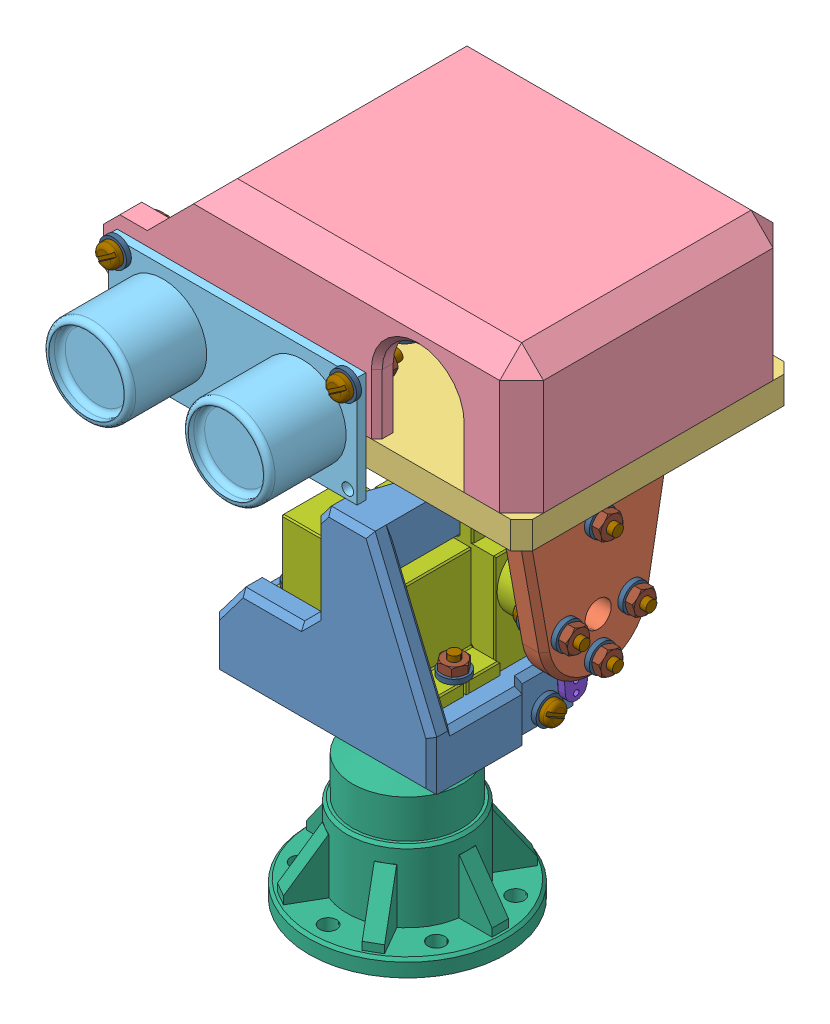
SolidWorks assembly headSub, configuration Default. Lengths in mm.
Overall size (76.5 110.09 65.6).
65 component instances, 11 part files, 135 mates.
Components (placement in the parent):
- headServoMount-1: headServoMount [Default] at (-6.1591 24.2018 19.2288) x (-1 0 0) z (0 0 1) size (39.75 36.12 28.6)
- headMount-1: headMount [Default] at (6.6839 24.3518 6.3351) x (0 -1 0) z (1 0 0) size (40 30 34)
- headBaseplate-1: headBaseplate [Default] at (24.6839 48.7958 -21.2212) x (-1 0 0) z (0 0 -1) size (60 5 50)
- headCanopy-1: headCanopy [Default] at (24.6839 78.7958 28.7788) x (-1 0 0) z (0 -1 0) size (76.5 50 25)
- usSensor-2: usSensor [Default] at (-49.3161 43.5958 28.7788) x (1 0 0) z (0 -1 0) size (45.5 15.6 26.2)
- mastMount-top-1: mastMount-top [Default] at (-11.9091 -31.2972 13.0788) size (36 28 36)
- sg90Servo-1: sg90Servo [Default] at (-6.1591 24.0708 19.2288) x (-1 0 0) z (0 0 1) size (32.7 29.37 12.3)
- sg90Servo-2: sg90Servo [Default] at (-24.2841 24.5458 6.9288) x (0 -1 0) z (0 0 1) size (32.7 29.37 12.3)
- sg90ServoHorn-star-1: sg90ServoHorn-star [Default] at (6.6839 20.6958 -2.0712) x (0 -1 0) z (0 0 -1) size (34.4 4 15.7)
- pan slot head_am-1: pan slot head_am [B18.6.7M - M3 x 0.5 x 16 Slotted PHMS --16C] at (-4.3161 42.4958 8.2249) x (0 1 0) z (0.26276 0 -0.964861) size (18.4 5.6 5.6)
- flat washer narrow_am-1: flat washer narrow_am [B18.22M - Plain washer, 3 mm, narrow] at (-4.3161 54.6958 8.2249) x (0 1 0) z (-0.26276 0 0.964861) size (0.9 7 7)
- flat washer narrow_am-2: flat washer narrow_am [B18.22M - Plain washer, 3 mm, narrow] at (-4.3161 45.7958 8.2249) x (0 1 0) z (-0.26276 0 0.964861) size (0.9 7 7)
- hex nut style 1_am-1: hex nut style 1_am [B18.2.4.1M - Hex nut, Style 1,  M3 x 0.5 --D-C] at (-4.3161 57.0958 8.2249) x (-0.26276 0 0.964861) z (0 1 0) size (5.5 6.35 2.4)
- pan slot head_am-2: pan slot head_am [B18.6.7M - M3 x 0.5 x 16 Slotted PHMS --16C] at (-17.3161 42.4958 8.2249) x (0 1 0) z (0.26276 0 -0.964861) size (18.4 5.6 5.6)
- flat washer narrow_am-3: flat washer narrow_am [B18.22M - Plain washer, 3 mm, narrow] at (-17.3161 54.6958 8.2249) x (0 1 0) z (-0.26276 0 0.964861) size (0.9 7 7)
- flat washer narrow_am-4: flat washer narrow_am [B18.22M - Plain washer, 3 mm, narrow] at (-17.3161 45.7958 8.2249) x (0 1 0) z (-0.26276 0 0.964861) size (0.9 7 7)
- hex nut style 1_am-2: hex nut style 1_am [B18.2.4.1M - Hex nut, Style 1,  M3 x 0.5 --D-C] at (-17.3161 57.0958 8.2249) x (-0.26276 0 0.964861) z (0 1 0) size (5.5 6.35 2.4)
- pan slot head_am-3: pan slot head_am [B18.6.7M - M3 x 0.5 x 16 Slotted PHMS --16C] at (-17.3161 42.4958 -2.7121) x (0 1 0) z (0.26276 0 -0.964861) size (18.4 5.6 5.6)
- flat washer narrow_am-5: flat washer narrow_am [B18.22M - Plain washer, 3 mm, narrow] at (-17.3161 54.6958 -2.7121) x (0 1 0) z (-0.26276 0 0.964861) size (0.9 7 7)
- flat washer narrow_am-6: flat washer narrow_am [B18.22M - Plain washer, 3 mm, narrow] at (-17.3161 45.7958 -2.7121) x (0 1 0) z (-0.26276 0 0.964861) size (0.9 7 7)
- hex nut style 1_am-3: hex nut style 1_am [B18.2.4.1M - Hex nut, Style 1,  M3 x 0.5 --D-C] at (-17.3161 57.0958 -2.7121) x (-0.26276 0 0.964861) z (0 1 0) size (5.5 6.35 2.4)
- pan slot head_am-4: pan slot head_am [B18.6.7M - M3 x 0.5 x 16 Slotted PHMS --16C] at (-4.3161 42.4958 -2.7121) x (0 1 0) z (0.26276 0 -0.964861) size (18.4 5.6 5.6)
- flat washer narrow_am-7: flat washer narrow_am [B18.22M - Plain washer, 3 mm, narrow] at (-4.3161 54.6958 -2.7121) x (0 1 0) z (-0.26276 0 0.964861) size (0.9 7 7)
- flat washer narrow_am-8: flat washer narrow_am [B18.22M - Plain washer, 3 mm, narrow] at (-4.3161 45.7958 -2.7121) x (0 1 0) z (-0.26276 0 0.964861) size (0.9 7 7)
- hex nut style 1_am-4: hex nut style 1_am [B18.2.4.1M - Hex nut, Style 1,  M3 x 0.5 --D-C] at (-4.3161 57.0958 -2.7121) x (-0.26276 0 0.964861) z (0 1 0) size (5.5 6.35 2.4)
- pan slot head_am-5: pan slot head_am [B18.6.7M - M2 x 0.4 x 16 Slotted PHMS --16C] at (3.4409 -0.9542 0.7788) x (-1 0 0) z (0 -0.479221 -0.877694) size (17.6 4 4)
- flat washer narrow_am-9: flat washer narrow_am [B18.22M - Plain washer, 2 mm, narrow] at (0.9409 -0.9542 0.7788) x (-1 0 0) z (0 -0.479221 -0.877694) size (0.9 5 5)
- flat washer narrow_am-10: flat washer narrow_am [B18.22M - Plain washer, 2 mm, narrow] at (-9.5591 -0.9542 0.7788) x (-1 0 0) z (0 -0.479221 -0.877694) size (0.9 5 5)
- hex nut style 1_am-5: hex nut style 1_am [B18.2.4.1M - Hex nut, Style 1,  M2 x 0.4 --D-C] at (-11.1591 -0.9542 0.7788) x (0 0.479221 0.877694) z (-1 0 0) size (4 4.62 1.6)
- pan slot head_am-7: pan slot head_am [B18.6.7M - M2 x 0.4 x 10 Slotted PHMS --10C] at (-3.6591 27.3458 0.7788) x (-1 0 0) z (0 -0.054009 -0.99854) size (11.6 4 4)
- flat washer narrow_am-13: flat washer narrow_am [B18.22M - Plain washer, 2 mm, narrow] at (-6.1591 27.3458 0.7788) x (-1 0 0) z (0 -0.054009 -0.99854) size (0.9 5 5)
- flat washer narrow_am-14: flat washer narrow_am [B18.22M - Plain washer, 2 mm, narrow] at (-12.5591 27.3458 0.7788) x (-1 0 0) z (0 -0.054009 -0.99854) size (0.9 5 5)
- hex nut style 1_am-7: hex nut style 1_am [B18.2.4.1M - Hex nut, Style 1,  M2 x 0.4 --D-C] at (-14.1591 27.3458 0.7788) x (0 0.054009 0.99854) z (-1 0 0) size (4 4.62 1.6)
- pan slot head_am-8: pan slot head_am [B18.6.7M - M2 x 0.4 x 10 Slotted PHMS --10C] at (-31.6591 10.9458 13.0788) x (0 -1 0) z (-0.98388 0 -0.178829) size (11.6 4 4)
- flat washer narrow_am-15: flat washer narrow_am [B18.22M - Plain washer, 2 mm, narrow] at (-31.6591 8.4458 13.0788) x (0 -1 0) z (-0.98388 0 -0.178829) size (0.9 5 5)
- flat washer narrow_am-16: flat washer narrow_am [B18.22M - Plain washer, 2 mm, narrow] at (-31.6591 2.0458 13.0788) x (0 -1 0) z (-0.98388 0 -0.178829) size (0.9 5 5)
- hex nut style 1_am-8: hex nut style 1_am [B18.2.4.1M - Hex nut, Style 1,  M2 x 0.4 --D-C] at (-31.6591 0.4458 13.0788) x (0.98388 0 0.178829) z (0 -1 0) size (4 4.62 1.6)
- pan slot head_am-9: pan slot head_am [B18.6.7M - M2 x 0.4 x 16 Slotted PHMS --16C] at (-3.3591 -5.6542 13.0788) x (0 1 0) z (-0.921484 0 -0.388417) size (17.6 4 4)
- flat washer narrow_am-17: flat washer narrow_am [B18.22M - Plain washer, 2 mm, narrow] at (-3.3591 -3.1542 13.0788) x (0 1 0) z (-0.921484 0 -0.388417) size (0.9 5 5)
- flat washer narrow_am-18: flat washer narrow_am [B18.22M - Plain washer, 2 mm, narrow] at (-3.3591 9.3458 13.0788) x (0 1 0) z (-0.970412 0 0.241457) size (0.9 5 5)
- hex nut style 1_am-9: hex nut style 1_am [B18.2.4.1M - Hex nut, Style 1,  M2 x 0.4 --D-C] at (-3.3591 10.9458 13.0788) x (0.921484 0 0.388417) z (0 1 0) size (4 4.62 1.6)
- flat washer narrow_am-19: flat washer narrow_am [B18.22M - Plain washer, 2 mm, narrow] at (5.2239 33.7958 0.7788) x (1 0 0) z (0 -0.958974 0.283495) size (0.9 5 5)
- flat washer narrow_am-20: flat washer narrow_am [B18.22M - Plain washer, 2 mm, narrow] at (11.5839 33.7958 0.7788) x (1 0 0) z (0 -0.958974 0.283495) size (0.9 5 5)
- hex nut style 1_am-10: hex nut style 1_am [B18.2.4.1M - Hex nut, Style 1,  M2 x 0.4 --D-C] at (13.1839 33.7958 0.7788) x (0 0.958974 -0.283495) z (1 0 0) size (4 4.62 1.6)
- pan slot head_am-10: pan slot head_am [B18.6.7M - M2 x 0.4 x 10 Slotted PHMS --10C] at (2.7239 33.7958 0.7788) x (1 0 0) z (0 -0.958974 0.283495) size (11.6 4 4)
- flat washer narrow_am-21: flat washer narrow_am [B18.22M - Plain washer, 2 mm, narrow] at (5.2239 18.7958 6.8788) x (1 0 0) z (0 -0.958974 0.283495) size (0.9 5 5)
- flat washer narrow_am-22: flat washer narrow_am [B18.22M - Plain washer, 2 mm, narrow] at (11.5839 18.7958 6.8788) x (1 0 0) z (0 -0.958974 0.283495) size (0.9 5 5)
- hex nut style 1_am-11: hex nut style 1_am [B18.2.4.1M - Hex nut, Style 1,  M2 x 0.4 --D-C] at (13.1839 18.7958 6.8788) x (0 0.958974 -0.283495) z (1 0 0) size (4 4.62 1.6)
- pan slot head_am-11: pan slot head_am [B18.6.7M - M2 x 0.4 x 10 Slotted PHMS --10C] at (2.7239 18.7958 6.8788) x (1 0 0) z (0 -0.958974 0.283495) size (11.6 4 4)
- flat washer narrow_am-23: flat washer narrow_am [B18.22M - Plain washer, 2 mm, narrow] at (5.2239 12.2958 0.7788) x (1 0 0) z (0 -0.958974 0.283495) size (0.9 5 5)
- flat washer narrow_am-24: flat washer narrow_am [B18.22M - Plain washer, 2 mm, narrow] at (11.5839 12.2958 0.7788) x (1 0 0) z (0 -0.958974 0.283495) size (0.9 5 5)
- hex nut style 1_am-12: hex nut style 1_am [B18.2.4.1M - Hex nut, Style 1,  M2 x 0.4 --D-C] at (13.1839 12.2958 0.7788) x (0 0.958974 -0.283495) z (1 0 0) size (4 4.62 1.6)
- pan slot head_am-12: pan slot head_am [B18.6.7M - M2 x 0.4 x 10 Slotted PHMS --10C] at (2.7239 12.2958 0.7788) x (1 0 0) z (0 -0.958974 0.283495) size (11.6 4 4)
- flat washer narrow_am-25: flat washer narrow_am [B18.22M - Plain washer, 2 mm, narrow] at (5.2239 18.7958 -5.3212) x (1 0 0) z (0 -0.958974 0.283495) size (0.9 5 5)
- flat washer narrow_am-26: flat washer narrow_am [B18.22M - Plain washer, 2 mm, narrow] at (11.5839 18.7958 -5.3212) x (1 0 0) z (0 -0.958974 0.283495) size (0.9 5 5)
- hex nut style 1_am-13: hex nut style 1_am [B18.2.4.1M - Hex nut, Style 1,  M2 x 0.4 --D-C] at (13.1839 18.7958 -5.3212) x (0 0.958974 -0.283495) z (1 0 0) size (4 4.62 1.6)
- pan slot head_am-13: pan slot head_am [B18.6.7M - M2 x 0.4 x 10 Slotted PHMS --10C] at (2.7239 18.7958 -5.3212) x (1 0 0) z (0 -0.958974 0.283495) size (11.6 4 4)
- flat washer narrow_am-27: flat washer narrow_am [B18.22M - Plain washer, 2 mm, narrow] at (-5.5161 62.0958 30.3788) x (0 0 -1) z (-0.825588 -0.564273 0) size (0.9 5 5)
- flat washer narrow_am-28: flat washer narrow_am [B18.22M - Plain washer, 2 mm, narrow] at (-5.5161 62.0958 24.8788) x (0 0 -1) z (-0.825588 -0.564273 0) size (0.9 5 5)
- hex nut style 1_am-14: hex nut style 1_am [B18.2.4.1M - Hex nut, Style 1,  M2 x 0.4 --D-C] at (-5.5161 62.0958 23.2788) x (0.825588 0.564273 0) z (0 0 -1) size (4 4.62 1.6)
- pan slot head_am-14: pan slot head_am [B18.6.7M - M2 x 0.4 x 10 Slotted PHMS --10C] at (-5.5161 62.0958 32.8788) x (0 0 -1) z (-0.825588 -0.564273 0) size (11.6 4 4)
- flat washer narrow_am-29: flat washer narrow_am [B18.22M - Plain washer, 2 mm, narrow] at (-47.6161 62.0958 30.3788) x (0 0 -1) z (-0.825588 -0.564273 0) size (0.9 5 5)
- flat washer narrow_am-30: flat washer narrow_am [B18.22M - Plain washer, 2 mm, narrow] at (-47.6161 62.0958 23.8788) x (0 0 -1) z (-0.825588 -0.564273 0) size (0.9 5 5)
- hex nut style 1_am-15: hex nut style 1_am [B18.2.4.1M - Hex nut, Style 1,  M2 x 0.4 --D-C] at (-47.6161 62.0958 22.2788) x (0.825588 0.564273 0) z (0 0 -1) size (4 4.62 1.6)
- pan slot head_am-15: pan slot head_am [B18.6.7M - M2 x 0.4 x 10 Slotted PHMS --10C] at (-47.6161 62.0958 32.8788) x (0 0 -1) z (-0.825588 -0.564273 0) size (11.6 4 4)
Mates (geometry in assembly coordinates):
- Parallel8: parallel aligned: plane of headMount-1 through (10.6839 24.3518 6.3351) normal (1 0 0); plane of headBaseplate-1 through (24.6839 53.7958 -21.2212) normal (1 0 0)
- Coincident41: coincident anti-aligned: plane of headMount-1 through (10.6839 48.7958 6.3351) normal (0 1 0); plane of headBaseplate-1 through (24.6839 48.7958 -21.2212) normal (0 -1 0)
- Coincident45: coincident anti-aligned: plane of headBaseplate-1 through (24.6839 53.7958 -21.2212) normal (0 1 0); plane of headCanopy-1 through (24.6839 53.7958 28.7788) normal (0 -1 0)
- Distance10: distance = 12 mm aligned: plane of headMount-1 through (-23.3161 24.3518 6.3351) normal (-1 0 0); plane of headBaseplate-1 through (-35.3161 53.7958 -21.2212) normal (-1 0 0)
- Distance11: distance = 13 mm aligned: plane of headBaseplate-1 through (24.6839 53.7958 28.7788) normal (0 0 1); plane of headMount-1 through (10.6839 24.3518 15.7788) normal (0 0 1)
- Concentric3: concentric anti-aligned: cylinder of headBaseplate-1 through (20.1839 51.7958 24.2788) axis (0 1 0) radius 1.55; cylinder of headCanopy-1 through (20.1839 55.7958 24.2788) axis (0 -1 0) radius 1.55
- Concentric4: concentric anti-aligned: cylinder of headBaseplate-1 through (-30.8161 51.7958 -16.7212) axis (0 1 0) radius 1.55; cylinder of headCanopy-1 through (-30.8161 55.7958 -16.7212) axis (0 -1 0) radius 1.55
- Coincident63: coincident anti-aligned: plane of headCanopy-1 through (-35.3161 73.7958 28.7788) normal (0 0 1); plane of usSensor-2 through (-49.3161 43.5958 28.7788) normal (0 0 -1)
- Distance17: distance = 15 mm aligned: plane of usSensor-2 through (-49.3161 63.7958 30.3788) normal (0 1 0); plane of headCanopy-1 through (24.6839 78.7958 28.7788) normal (0 1 0)
- Distance18: distance = 2 mm aligned: plane of usSensor-2 through (-3.8161 43.5958 30.3788) normal (1 0 0); plane of headCanopy-1 through (-1.8161 78.7958 -21.2222) normal (1 0 0)
- Coincident66: coincident anti-aligned: plane of headServoMount-1 through (-6.1591 24.2018 19.2288) normal (0 0 -1); plane of sg90Servo-1 through (-6.1591 1.8458 19.2288) normal (0 0 1)
- Coincident67: coincident anti-aligned: plane of sg90Servo-1 through (-6.1591 1.8458 6.9288) normal (0 0 -1); plane of sg90Servo-2 through (-2.0591 24.5458 6.9288) normal (0 0 1)
- Coincident68: coincident aligned: plane of sg90Servo-1 through (-6.1591 1.8458 19.2288) normal (1 0 0); plane of sg90Servo-2 through (-6.1591 -3.1542 6.9288) normal (1 0 0)
- Coincident69: coincident aligned: plane of sg90Servo-1 through (-6.1591 1.8458 19.2288) normal (0 -1 0); plane of sg90Servo-2 through (-2.0591 1.8458 6.9288) normal (0 -1 0)
- Concentric8: concentric anti-aligned: cylinder of headServoMount-1 through (-31.6591 -3.1552 13.0788) axis (0 1 0) radius 1.1; cylinder of sg90Servo-1 through (-31.6591 24.0719 13.0788) axis (0 -1 0) radius 1.1
- Coincident71: coincident anti-aligned: plane of headServoMount-1 through (-6.1591 5.9458 -1.8849) normal (0 1 0); plane of sg90Servo-1 through (-33.8591 5.9458 19.2288) normal (0 -1 0)
- Concentric9: concentric aligned: cylinder of mastMount-top-1 through (-11.9091 -5.2972 13.0788) axis (0 1 0) radius 2.4; cylinder of sg90Servo-1 through (-11.9091 -5.2972 13.0788) axis (0 1 0) radius 1.984
- Coincident72: coincident anti-aligned: plane of mastMount-top-1 through (-11.9091 -5.2972 13.0788) normal (0 1 0); plane of sg90Servo-1 through (-11.9091 -5.2972 13.0788) normal (0 -1 0)
- Coincident73: coincident anti-aligned: plane of headMount-1 through (6.6839 24.3518 6.3351) normal (-1 0 0); plane of sg90ServoHorn-star-1 through (6.6839 20.6958 -2.0712) normal (1 0 0)
- Parallel9: parallel anti-aligned: plane of headMount-1 through (-23.3161 45.7958 -14.2212) normal (0 -1 0); plane of sg90ServoHorn-star-1 through (5.2239 20.6958 -2.0712) normal (0 1 0)
- Concentric12: concentric aligned: cylinder of headMount-1 through (10.6849 18.7958 0.7788) axis (-1 0 0) radius 2.4; cylinder of sg90ServoHorn-star-1 through (6.6849 18.7958 0.7788) axis (-1 0 0) radius 1.2
- Concentric13: concentric aligned: cylinder of sg90Servo-2 through (5.0839 18.7958 0.7788) axis (-1 0 0) radius 1.984; cylinder of sg90ServoHorn-star-1 through (5.0839 18.7958 0.7788) axis (-1 0 0) radius 2.4
- Coincident78: coincident anti-aligned: plane of sg90Servo-2 through (5.0839 18.7958 0.7788) normal (1 0 0); plane of sg90ServoHorn-star-1 through (5.0839 18.7958 0.7788) normal (-1 0 0)
- Concentric14: concentric aligned: cylinder of pan slot head_am-1 through (-4.3161 17.0958 8.2249) axis (0 -1 0) radius 1.5; circle of flat washer narrow_am-2
- Coincident79: coincident anti-aligned: plane of pan slot head_am-1 through (-2.8688 44.8958 8.619) normal (0 1 0); plane of flat washer narrow_am-2 through (-7.6931 44.8958 7.3052) normal (0 -1 0)
- Concentric15: concentric aligned: cylinder of pan slot head_am-1 through (-4.3161 17.0958 8.2249) axis (0 -1 0) radius 1.5; cylinder of flat washer narrow_am-1 through (-4.3161 19.7708 8.2249) axis (0 -1 0) radius 1.84
- Concentric16: concentric anti-aligned: cylinder of pan slot head_am-1 through (-4.3161 17.0958 8.2249) axis (0 -1 0) radius 1.5; cylinder of hex nut style 1_am-1 through (-4.3161 54.6958 8.2249) axis (0 1 0) radius 1.25
- Coincident80: coincident anti-aligned: plane of flat washer narrow_am-1 through (-6.0914 54.6958 7.7414) normal (0 1 0); plane of hex nut style 1_am-1 through (-1.2522 54.6958 9.0593) normal (0 -1 0)
- Concentric17: concentric aligned: cylinder of headMount-1 through (-4.3161 48.7968 8.2249) axis (0 -1 0) radius 1.55; cylinder of pan slot head_am-1 through (-4.3161 17.0958 8.2249) axis (0 -1 0) radius 1.5
- Coincident81: coincident anti-aligned: plane of headMount-1 through (-23.3161 45.7958 -14.2212) normal (0 -1 0); plane of flat washer narrow_am-2 through (-6.0914 45.7958 7.7414) normal (0 1 0)
- Coincident82: coincident anti-aligned: plane of headBaseplate-1 through (24.6839 53.7958 -21.2212) normal (0 1 0); plane of flat washer narrow_am-1 through (-7.6931 53.7958 7.3052) normal (0 -1 0)
- Concentric18: concentric aligned: cylinder of pan slot head_am-2 through (-17.3161 17.0958 8.2249) axis (0 -1 0) radius 1.5; circle of flat washer narrow_am-4
- Coincident83: coincident anti-aligned: plane of pan slot head_am-2 through (-15.8688 44.8958 8.619) normal (0 1 0); plane of flat washer narrow_am-4 through (-20.6931 44.8958 7.3052) normal (0 -1 0)
- Concentric19: concentric aligned: cylinder of pan slot head_am-2 through (-17.3161 17.0958 8.2249) axis (0 -1 0) radius 1.5; cylinder of flat washer narrow_am-3 through (-17.3161 19.7708 8.2249) axis (0 -1 0) radius 1.84
- Concentric20: concentric anti-aligned: cylinder of pan slot head_am-2 through (-17.3161 17.0958 8.2249) axis (0 -1 0) radius 1.5; cylinder of hex nut style 1_am-2 through (-17.3161 54.6958 8.2249) axis (0 1 0) radius 1.25
- Coincident84: coincident anti-aligned: plane of flat washer narrow_am-3 through (-19.0914 54.6958 7.7414) normal (0 1 0); plane of hex nut style 1_am-2 through (-14.2522 54.6958 9.0593) normal (0 -1 0)
- Concentric21: concentric aligned: cylinder of headMount-1 through (-17.3161 48.7968 8.2249) axis (0 -1 0) radius 1.55; cylinder of pan slot head_am-2 through (-17.3161 17.0958 8.2249) axis (0 -1 0) radius 1.5
- Coincident85: coincident anti-aligned: plane of headMount-1 through (-23.3161 45.7958 -14.2212) normal (0 -1 0); plane of flat washer narrow_am-4 through (-19.0914 45.7958 7.7414) normal (0 1 0)
- Coincident86: coincident anti-aligned: plane of headBaseplate-1 through (24.6839 53.7958 -21.2212) normal (0 1 0); plane of flat washer narrow_am-3 through (-20.6931 53.7958 7.3052) normal (0 -1 0)
- Concentric22: concentric aligned: cylinder of pan slot head_am-3 through (-17.3161 17.0958 -2.7121) axis (0 -1 0) radius 1.5; circle of flat washer narrow_am-6
- Coincident87: coincident anti-aligned: plane of pan slot head_am-3 through (-15.8688 44.8958 -2.318) normal (0 1 0); plane of flat washer narrow_am-6 through (-20.6931 44.8958 -3.6318) normal (0 -1 0)
- Concentric23: concentric aligned: cylinder of pan slot head_am-3 through (-17.3161 17.0958 -2.7121) axis (0 -1 0) radius 1.5; cylinder of flat washer narrow_am-5 through (-17.3161 19.7708 -2.7121) axis (0 -1 0) radius 1.84
- Concentric24: concentric anti-aligned: cylinder of pan slot head_am-3 through (-17.3161 17.0958 -2.7121) axis (0 -1 0) radius 1.5; cylinder of hex nut style 1_am-3 through (-17.3161 54.6958 -2.7121) axis (0 1 0) radius 1.25
- Coincident88: coincident anti-aligned: plane of flat washer narrow_am-5 through (-19.0914 54.6958 -3.1956) normal (0 1 0); plane of hex nut style 1_am-3 through (-14.2522 54.6958 -1.8778) normal (0 -1 0)
- Concentric25: concentric aligned: cylinder of headMount-1 through (-17.3161 48.7968 -2.7121) axis (0 -1 0) radius 1.55; cylinder of pan slot head_am-3 through (-17.3161 17.0958 -2.7121) axis (0 -1 0) radius 1.5
- Coincident89: coincident anti-aligned: plane of headMount-1 through (-23.3161 45.7958 -14.2212) normal (0 -1 0); plane of flat washer narrow_am-6 through (-19.0914 45.7958 -3.1956) normal (0 1 0)
- Coincident90: coincident anti-aligned: plane of headBaseplate-1 through (24.6839 53.7958 -21.2212) normal (0 1 0); plane of flat washer narrow_am-5 through (-20.6931 53.7958 -3.6318) normal (0 -1 0)
- Concentric26: concentric aligned: cylinder of pan slot head_am-4 through (-4.3161 17.0958 -2.7121) axis (0 -1 0) radius 1.5; circle of flat washer narrow_am-8
- Coincident91: coincident anti-aligned: plane of pan slot head_am-4 through (-2.8688 44.8958 -2.318) normal (0 1 0); plane of flat washer narrow_am-8 through (-7.6931 44.8958 -3.6318) normal (0 -1 0)
- Concentric27: concentric aligned: cylinder of pan slot head_am-4 through (-4.3161 17.0958 -2.7121) axis (0 -1 0) radius 1.5; cylinder of flat washer narrow_am-7 through (-4.3161 19.7708 -2.7121) axis (0 -1 0) radius 1.84
- Concentric28: concentric anti-aligned: cylinder of pan slot head_am-4 through (-4.3161 17.0958 -2.7121) axis (0 -1 0) radius 1.5; cylinder of hex nut style 1_am-4 through (-4.3161 54.6958 -2.7121) axis (0 1 0) radius 1.25
- Coincident92: coincident anti-aligned: plane of flat washer narrow_am-7 through (-6.0914 54.6958 -3.1956) normal (0 1 0); plane of hex nut style 1_am-4 through (-1.2522 54.6958 -1.8778) normal (0 -1 0)
- Concentric29: concentric aligned: cylinder of headMount-1 through (-4.3161 48.7968 -2.7121) axis (0 -1 0) radius 1.55; cylinder of pan slot head_am-4 through (-4.3161 17.0958 -2.7121) axis (0 -1 0) radius 1.5
- Coincident93: coincident anti-aligned: plane of headMount-1 through (-23.3161 45.7958 -14.2212) normal (0 -1 0); plane of flat washer narrow_am-8 through (-6.0914 45.7958 -3.1956) normal (0 1 0)
- Coincident94: coincident anti-aligned: plane of headBaseplate-1 through (24.6839 53.7958 -21.2212) normal (0 1 0); plane of flat washer narrow_am-7 through (-7.6931 53.7958 -3.6318) normal (0 -1 0)
- Concentric30: concentric aligned: cylinder of pan slot head_am-5 through (28.8409 -0.9542 0.7788) axis (1 0 0) radius 1; cylinder of flat washer narrow_am-9 through (35.8659 -0.9542 0.7788) axis (1 0 0) radius 1.32
- Concentric32: concentric aligned: cylinder of pan slot head_am-5 through (28.8409 -0.9542 0.7788) axis (1 0 0) radius 1; cylinder of flat washer narrow_am-10 through (25.3659 -0.9542 0.7788) axis (1 0 0) radius 1.32
- Coincident95: coincident anti-aligned: plane of pan slot head_am-5 through (1.8409 -0.0765 0.2996) normal (-1 0 0); plane of flat washer narrow_am-9 through (1.8409 1.2401 -0.4192) normal (1 0 0)
- Concentric33: concentric anti-aligned: cylinder of pan slot head_am-5 through (28.8409 -0.9542 0.7788) axis (1 0 0) radius 1; cylinder of hex nut style 1_am-5 through (-9.5591 -0.9542 0.7788) axis (-1 0 0) radius 0.8
- Coincident96: coincident anti-aligned: plane of flat washer narrow_am-10 through (-9.5591 0.2044 0.1463) normal (-1 0 0); plane of hex nut style 1_am-5 through (-9.5591 1.0728 -0.3279) normal (1 0 0)
- Concentric34: concentric anti-aligned: cylinder of headServoMount-1 through (2.6044 -0.9542 0.7788) axis (-1 0 0) radius 1.1; cylinder of pan slot head_am-5 through (28.8409 -0.9542 0.7788) axis (1 0 0) radius 1
- Coincident97: coincident anti-aligned: plane of headServoMount-1 through (0.9409 24.2018 -16.9133) normal (1 0 0); plane of flat washer narrow_am-9 through (0.9409 0.2044 0.1463) normal (-1 0 0)
- Coincident98: coincident anti-aligned: plane of sg90Servo-2 through (-8.6591 -3.1542 6.9288) normal (-1 0 0); plane of flat washer narrow_am-10 through (-8.6591 1.2401 -0.4192) normal (1 0 0)
- Concentric39: concentric aligned: cylinder of pan slot head_am-7 through (21.7409 27.3458 0.7788) axis (1 0 0) radius 1; cylinder of flat washer narrow_am-13 through (28.7659 27.3458 0.7788) axis (1 0 0) radius 1.32
- Concentric40: concentric aligned: cylinder of pan slot head_am-7 through (21.7409 27.3458 0.7788) axis (1 0 0) radius 1; cylinder of flat washer narrow_am-14 through (22.3659 27.3458 0.7788) axis (1 0 0) radius 1.32
- Coincident102: coincident anti-aligned: plane of pan slot head_am-7 through (-5.2591 28.3444 0.7248) normal (-1 0 0); plane of flat washer narrow_am-13 through (-5.2591 29.8422 0.6438) normal (1 0 0)
- Concentric41: concentric anti-aligned: cylinder of pan slot head_am-7 through (21.7409 27.3458 0.7788) axis (1 0 0) radius 1; cylinder of hex nut style 1_am-7 through (-12.5591 27.3458 0.7788) axis (-1 0 0) radius 0.8
- Coincident103: coincident anti-aligned: plane of flat washer narrow_am-14 through (-12.5591 28.6639 0.7075) normal (-1 0 0); plane of hex nut style 1_am-7 through (-12.5591 29.6519 0.6541) normal (1 0 0)
- Concentric42: concentric aligned: cylinder of headServoMount-1 through (-37.1476 27.3458 0.7788) axis (1 0 0) radius 1.1; cylinder of pan slot head_am-7 through (21.7409 27.3458 0.7788) axis (1 0 0) radius 1
- Coincident104: coincident anti-aligned: plane of sg90Servo-2 through (-6.1591 29.5458 6.9288) normal (1 0 0); plane of flat washer narrow_am-13 through (-6.1591 28.6639 0.7075) normal (-1 0 0)
- Coincident105: coincident anti-aligned: plane of headServoMount-1 through (-11.6591 24.2018 -14.0731) normal (-1 0 0); plane of flat washer narrow_am-14 through (-11.6591 29.8422 0.6438) normal (1 0 0)
- Concentric43: concentric aligned: cylinder of pan slot head_am-8 through (-31.6591 36.3458 13.0788) axis (0 1 0) radius 1; cylinder of flat washer narrow_am-15 through (-31.6591 43.3708 13.0788) axis (0 1 0) radius 1.32
- Concentric44: concentric aligned: cylinder of pan slot head_am-8 through (-31.6591 36.3458 13.0788) axis (0 1 0) radius 1; cylinder of flat washer narrow_am-16 through (-31.6591 36.9708 13.0788) axis (0 1 0) radius 1.32
- Coincident106: coincident anti-aligned: plane of pan slot head_am-8 through (-31.8379 9.3458 14.0627) normal (0 -1 0); plane of flat washer narrow_am-15 through (-32.1061 9.3458 15.5385) normal (0 1 0)
- Concentric45: concentric anti-aligned: cylinder of pan slot head_am-8 through (-31.6591 36.3458 13.0788) axis (0 1 0) radius 1; cylinder of hex nut style 1_am-8 through (-31.6591 2.0458 13.0788) axis (0 -1 0) radius 0.8
- Coincident107: coincident anti-aligned: plane of flat washer narrow_am-16 through (-31.8951 2.0458 14.3776) normal (0 -1 0); plane of hex nut style 1_am-8 through (-32.0721 2.0458 15.351) normal (0 1 0)
- Concentric46: concentric aligned: cylinder of headServoMount-1 through (-31.6591 -3.1552 13.0788) axis (0 1 0) radius 1.1; cylinder of pan slot head_am-8 through (-31.6591 36.3458 13.0788) axis (0 1 0) radius 1
- Coincident108: coincident anti-aligned: plane of sg90Servo-1 through (-33.8591 8.4458 19.2288) normal (0 1 0); plane of flat washer narrow_am-15 through (-31.8951 8.4458 14.3776) normal (0 -1 0)
- Coincident109: coincident anti-aligned: plane of headServoMount-1 through (-6.1591 2.9458 -1.8849) normal (0 -1 0); plane of flat washer narrow_am-16 through (-32.1061 2.9458 15.5385) normal (0 1 0)
- Concentric47: concentric aligned: cylinder of pan slot head_am-9 through (-3.3591 -31.0542 13.0788) axis (0 -1 0) radius 1; cylinder of flat washer narrow_am-17 through (-3.3591 -38.0792 13.0788) axis (0 -1 0) radius 1.32
- Concentric48: concentric aligned: cylinder of pan slot head_am-9 through (-3.3591 -31.0542 13.0788) axis (0 -1 0) radius 1; cylinder of flat washer narrow_am-18 through (-3.3591 -25.5792 13.0788) axis (0 -1 0) radius 1.32
- Coincident110: coincident anti-aligned: plane of pan slot head_am-9 through (-2.9707 -4.0542 12.1574) normal (0 1 0); plane of flat washer narrow_am-17 through (-2.388 -4.0542 10.7751) normal (0 -1 0)
- Concentric49: concentric anti-aligned: cylinder of pan slot head_am-9 through (-3.3591 -31.0542 13.0788) axis (0 -1 0) radius 1; cylinder of hex nut style 1_am-9 through (-3.3591 9.3458 13.0788) axis (0 1 0) radius 0.8
- Coincident111: coincident anti-aligned: plane of flat washer narrow_am-18 through (-3.6778 9.3458 11.7979) normal (0 1 0); plane of hex nut style 1_am-9 through (-2.4621 9.3458 10.9508) normal (0 -1 0)
- Concentric50: concentric anti-aligned: cylinder of headServoMount-1 through (-3.3591 -3.1552 13.0788) axis (0 1 0) radius 1.1; cylinder of pan slot head_am-9 through (-3.3591 -31.0542 13.0788) axis (0 -1 0) radius 1
- Coincident112: coincident anti-aligned: plane of headServoMount-1 through (-6.1591 -3.1542 23.2288) normal (0 -1 0); plane of flat washer narrow_am-17 through (-2.8464 -3.1542 11.8625) normal (0 1 0)
- Coincident113: coincident anti-aligned: plane of sg90Servo-1 through (-1.1591 8.4458 19.2288) normal (0 1 0); plane of flat washer narrow_am-18 through (-3.9627 8.4458 10.6528) normal (0 -1 0)
- Concentric51: concentric aligned: cylinder of flat washer narrow_am-19 through (-29.7011 33.7958 0.7788) axis (-1 0 0) radius 1.32; cylinder of pan slot head_am-10 through (-22.6761 33.7958 0.7788) axis (-1 0 0) radius 1
- Concentric52: concentric aligned: cylinder of flat washer narrow_am-20 through (-23.3411 33.7958 0.7788) axis (-1 0 0) radius 1.32; cylinder of pan slot head_am-10 through (-22.6761 33.7958 0.7788) axis (-1 0 0) radius 1
- Coincident114: coincident anti-aligned: plane of flat washer narrow_am-19 through (4.3239 34.5046 3.1763) normal (-1 0 0); plane of pan slot head_am-10 through (4.3239 34.0793 1.7378) normal (1 0 0)
- Concentric53: concentric anti-aligned: cylinder of hex nut style 1_am-10 through (11.5839 33.7958 0.7788) axis (1 0 0) radius 0.8; cylinder of pan slot head_am-10 through (-22.6761 33.7958 0.7788) axis (-1 0 0) radius 1
- Coincident115: coincident anti-aligned: plane of flat washer narrow_am-20 through (11.5839 34.17 2.0447) normal (1 0 0); plane of hex nut style 1_am-10 through (11.5839 34.4505 2.9935) normal (-1 0 0)
- Concentric54: concentric aligned: cylinder of headMount-1 through (10.6849 33.7958 0.7788) axis (-1 0 0) radius 0.5; cylinder of pan slot head_am-10 through (-22.6761 33.7958 0.7788) axis (-1 0 0) radius 1
- Coincident116: coincident anti-aligned: plane of sg90ServoHorn-star-1 through (5.2239 20.6958 -2.0712) normal (-1 0 0); plane of flat washer narrow_am-19 through (5.2239 34.17 2.0447) normal (1 0 0)
- Coincident117: coincident anti-aligned: plane of headMount-1 through (10.6839 24.3518 6.3351) normal (1 0 0); plane of flat washer narrow_am-20 through (10.6839 34.5046 3.1763) normal (-1 0 0)
- Concentric55: concentric aligned: cylinder of flat washer narrow_am-21 through (-29.7011 18.7958 6.8788) axis (-1 0 0) radius 1.32; cylinder of pan slot head_am-11 through (-22.6761 18.7958 6.8788) axis (-1 0 0) radius 1
- Concentric56: concentric aligned: cylinder of flat washer narrow_am-22 through (-23.3411 18.7958 6.8788) axis (-1 0 0) radius 1.32; cylinder of pan slot head_am-11 through (-22.6761 18.7958 6.8788) axis (-1 0 0) radius 1
- Coincident118: coincident anti-aligned: plane of flat washer narrow_am-21 through (4.3239 19.5046 9.2763) normal (-1 0 0); plane of pan slot head_am-11 through (4.3239 19.0793 7.8378) normal (1 0 0)
- Concentric57: concentric anti-aligned: cylinder of hex nut style 1_am-11 through (11.5839 18.7958 6.8788) axis (1 0 0) radius 0.8; cylinder of pan slot head_am-11 through (-22.6761 18.7958 6.8788) axis (-1 0 0) radius 1
- Coincident119: coincident anti-aligned: plane of flat washer narrow_am-22 through (11.5839 19.17 8.1447) normal (1 0 0); plane of hex nut style 1_am-11 through (11.5839 19.4505 9.0935) normal (-1 0 0)
- Concentric58: concentric aligned: cylinder of headMount-1 through (10.6849 18.7958 6.8788) axis (-1 0 0) radius 0.5; cylinder of pan slot head_am-11 through (-22.6761 18.7958 6.8788) axis (-1 0 0) radius 1
- Coincident120: coincident anti-aligned: plane of sg90ServoHorn-star-1 through (5.2239 20.6958 -2.0712) normal (-1 0 0); plane of flat washer narrow_am-21 through (5.2239 19.17 8.1447) normal (1 0 0)
- Coincident121: coincident anti-aligned: plane of headMount-1 through (10.6839 24.3518 6.3351) normal (1 0 0); plane of flat washer narrow_am-22 through (10.6839 19.5046 9.2763) normal (-1 0 0)
- Concentric59: concentric aligned: cylinder of flat washer narrow_am-23 through (-29.7011 12.2958 0.7788) axis (-1 0 0) radius 1.32; cylinder of pan slot head_am-12 through (-22.6761 12.2958 0.7788) axis (-1 0 0) radius 1
- Concentric60: concentric aligned: cylinder of flat washer narrow_am-24 through (-23.3411 12.2958 0.7788) axis (-1 0 0) radius 1.32; cylinder of pan slot head_am-12 through (-22.6761 12.2958 0.7788) axis (-1 0 0) radius 1
- Coincident122: coincident anti-aligned: plane of flat washer narrow_am-23 through (4.3239 13.0046 3.1763) normal (-1 0 0); plane of pan slot head_am-12 through (4.3239 12.5793 1.7378) normal (1 0 0)
- Concentric61: concentric anti-aligned: cylinder of hex nut style 1_am-12 through (11.5839 12.2958 0.7788) axis (1 0 0) radius 0.8; cylinder of pan slot head_am-12 through (-22.6761 12.2958 0.7788) axis (-1 0 0) radius 1
- Coincident123: coincident anti-aligned: plane of flat washer narrow_am-24 through (11.5839 12.67 2.0447) normal (1 0 0); plane of hex nut style 1_am-12 through (11.5839 12.9505 2.9935) normal (-1 0 0)
- Concentric62: concentric aligned: cylinder of headMount-1 through (10.6849 12.2958 0.7788) axis (-1 0 0) radius 0.5; cylinder of pan slot head_am-12 through (-22.6761 12.2958 0.7788) axis (-1 0 0) radius 1
- Coincident124: coincident anti-aligned: plane of sg90ServoHorn-star-1 through (5.2239 20.6958 -2.0712) normal (-1 0 0); plane of flat washer narrow_am-23 through (5.2239 12.67 2.0447) normal (1 0 0)
- Coincident125: coincident anti-aligned: plane of headMount-1 through (10.6839 24.3518 6.3351) normal (1 0 0); plane of flat washer narrow_am-24 through (10.6839 13.0046 3.1763) normal (-1 0 0)
- Concentric63: concentric aligned: cylinder of flat washer narrow_am-25 through (-29.7011 18.7958 -5.3212) axis (-1 0 0) radius 1.32; cylinder of pan slot head_am-13 through (-22.6761 18.7958 -5.3212) axis (-1 0 0) radius 1
- Concentric64: concentric aligned: cylinder of flat washer narrow_am-26 through (-23.3411 18.7958 -5.3212) axis (-1 0 0) radius 1.32; cylinder of pan slot head_am-13 through (-22.6761 18.7958 -5.3212) axis (-1 0 0) radius 1
- Coincident126: coincident anti-aligned: plane of flat washer narrow_am-25 through (4.3239 19.5046 -2.9237) normal (-1 0 0); plane of pan slot head_am-13 through (4.3239 19.0793 -4.3622) normal (1 0 0)
- Concentric65: concentric anti-aligned: cylinder of hex nut style 1_am-13 through (11.5839 18.7958 -5.3212) axis (1 0 0) radius 0.8; cylinder of pan slot head_am-13 through (-22.6761 18.7958 -5.3212) axis (-1 0 0) radius 1
- Coincident127: coincident anti-aligned: plane of flat washer narrow_am-26 through (11.5839 19.17 -4.0553) normal (1 0 0); plane of hex nut style 1_am-13 through (11.5839 19.4505 -3.1065) normal (-1 0 0)
- Concentric66: concentric aligned: cylinder of headMount-1 through (10.6849 18.7958 -5.3212) axis (-1 0 0) radius 0.5; cylinder of pan slot head_am-13 through (-22.6761 18.7958 -5.3212) axis (-1 0 0) radius 1
- Coincident128: coincident anti-aligned: plane of sg90ServoHorn-star-1 through (5.2239 20.6958 -2.0712) normal (-1 0 0); plane of flat washer narrow_am-25 through (5.2239 19.17 -4.0553) normal (1 0 0)
- Coincident129: coincident anti-aligned: plane of headMount-1 through (10.6839 24.3518 6.3351) normal (1 0 0); plane of flat washer narrow_am-26 through (10.6839 19.5046 -2.9237) normal (-1 0 0)
- Concentric67: concentric aligned: cylinder of flat washer narrow_am-27 through (-5.5161 62.0958 65.3038) axis (0 0 1) radius 1.32; cylinder of pan slot head_am-14 through (-5.5161 62.0958 58.2788) axis (0 0 1) radius 1
- Concentric68: concentric aligned: cylinder of flat washer narrow_am-28 through (-5.5161 62.0958 59.8038) axis (0 0 1) radius 1.32; cylinder of pan slot head_am-14 through (-5.5161 62.0958 58.2788) axis (0 0 1) radius 1
- Coincident130: coincident anti-aligned: plane of flat washer narrow_am-27 through (-4.1054 60.0319 31.2788) normal (0 0 1); plane of pan slot head_am-14 through (-4.9518 61.2702 31.2788) normal (0 0 -1)
- Concentric69: concentric anti-aligned: cylinder of hex nut style 1_am-14 through (-5.5161 62.0958 24.8788) axis (0 0 -1) radius 0.8; cylinder of pan slot head_am-14 through (-5.5161 62.0958 58.2788) axis (0 0 1) radius 1
- Coincident131: coincident anti-aligned: plane of flat washer narrow_am-28 through (-4.7712 61.0061 24.8788) normal (0 0 -1); plane of hex nut style 1_am-14 through (-4.2129 60.1892 24.8788) normal (0 0 1)
- Concentric70: concentric aligned: cylinder of usSensor-2 through (-5.5161 62.0958 28.7778) axis (0 0 1) radius 1.05; cylinder of pan slot head_am-14 through (-5.5161 62.0958 58.2788) axis (0 0 1) radius 1
- Coincident132: coincident anti-aligned: plane of usSensor-2 through (-49.3161 43.5958 30.3788) normal (0 0 1); plane of flat washer narrow_am-27 through (-4.7712 61.0061 30.3788) normal (0 0 -1)
- Coincident133: coincident anti-aligned: plane of headCanopy-1 through (24.6839 53.7958 25.7788) normal (0 0 -1); plane of flat washer narrow_am-28 through (-4.1054 60.0319 25.7788) normal (0 0 1)
- Concentric71: concentric aligned: cylinder of flat washer narrow_am-29 through (-47.6161 62.0958 65.3038) axis (0 0 1) radius 1.32; cylinder of pan slot head_am-15 through (-47.6161 62.0958 58.2788) axis (0 0 1) radius 1
- Concentric72: concentric aligned: cylinder of flat washer narrow_am-30 through (-47.6161 62.0958 58.8038) axis (0 0 1) radius 1.32; cylinder of pan slot head_am-15 through (-47.6161 62.0958 58.2788) axis (0 0 1) radius 1
- Coincident134: coincident anti-aligned: plane of flat washer narrow_am-29 through (-46.2054 60.0319 31.2788) normal (0 0 1); plane of pan slot head_am-15 through (-47.0518 61.2702 31.2788) normal (0 0 -1)
- Concentric73: concentric anti-aligned: cylinder of hex nut style 1_am-15 through (-47.6161 62.0958 23.8788) axis (0 0 -1) radius 0.8; cylinder of pan slot head_am-15 through (-47.6161 62.0958 58.2788) axis (0 0 1) radius 1
- Coincident135: coincident anti-aligned: plane of flat washer narrow_am-30 through (-46.8712 61.0061 23.8788) normal (0 0 -1); plane of hex nut style 1_am-15 through (-46.3129 60.1892 23.8788) normal (0 0 1)
- Concentric74: concentric aligned: cylinder of usSensor-2 through (-47.6161 62.0958 28.7778) axis (0 0 1) radius 1.05; cylinder of pan slot head_am-15 through (-47.6161 62.0958 58.2788) axis (0 0 1) radius 1
- Coincident136: coincident anti-aligned: plane of usSensor-2 through (-49.3161 43.5958 30.3788) normal (0 0 1); plane of flat washer narrow_am-29 through (-46.8712 61.0061 30.3788) normal (0 0 -1)
- Coincident137: coincident anti-aligned: plane of headCanopy-1 through (24.6839 78.7958 24.7788) normal (0 0 -1); plane of flat washer narrow_am-30 through (-46.2054 60.0319 24.7788) normal (0 0 1)
